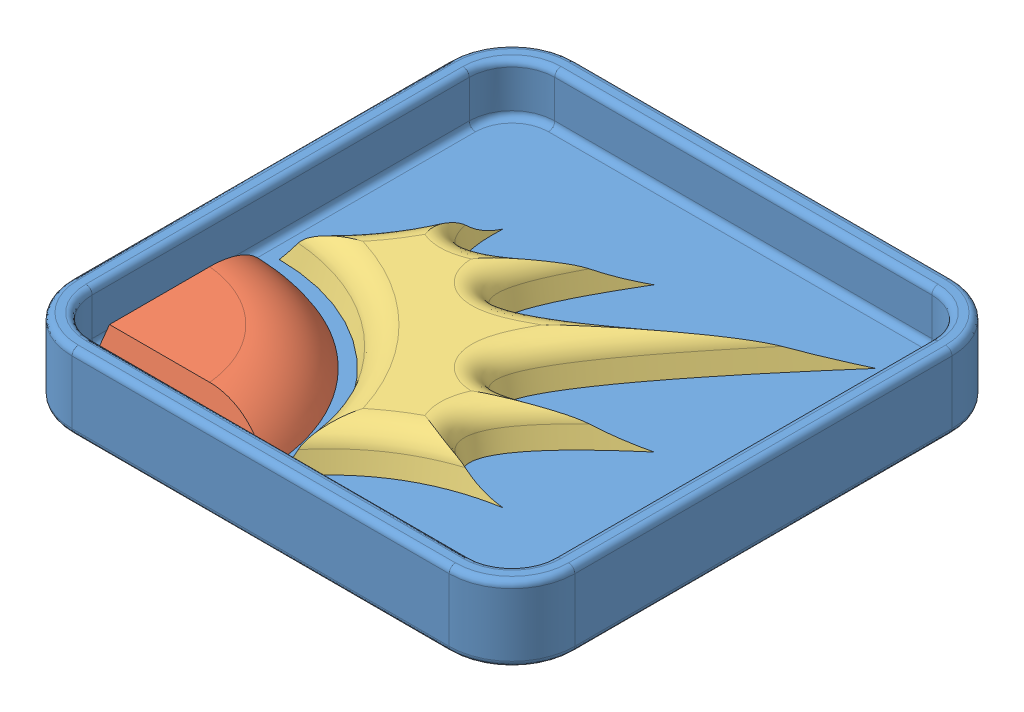
SolidWorks assembly Assem5, configuration Default. Lengths in mm.
Overall size (40 6 40).
3 component instances, 3 part files, 4 mates.
Components (placement in the parent):
- Tile-1: Tile [Default] at (14.7969 17.4505 31.062) size (40 6 40)
- SolarStorm-1: SolarStorm [Default] at (14.8586 19.4505 30.662) size (35 3.85 35)
- SolarStorm_B-1: SolarStorm_B [Default] at (14.9062 19.4505 30.662) size (35.67 3.78 35.67)
Mates (geometry in assembly coordinates):
- Coincident1: coincident anti-aligned: plane of Tile-1 through (-0.2031 19.4505 46.062) normal (0 1 0); plane of SolarStorm-1 through (-2.1856 19.4505 47.7062) normal (0 -1 0)
- Coincident2: coincident anti-aligned: line of Tile-1 through (29.7969 19.4505 13.162) axis (-1 0 0); line of SolarStorm-1 through (-2.6414 19.4505 13.162) axis (1 0 0)
- Coincident3: coincident anti-aligned: plane of Tile-1 through (-0.2031 19.4505 46.062) normal (0 1 0); plane of SolarStorm_B-1 through (14.9062 19.4505 30.662) normal (0 -1 0)
- Coincident4: coincident aligned: line of SolarStorm-1 through (-2.6414 19.4505 13.162) axis (1 0 0); line of SolarStorm_B-1 through (-2.5938 19.4505 13.162) axis (1 0 0)
